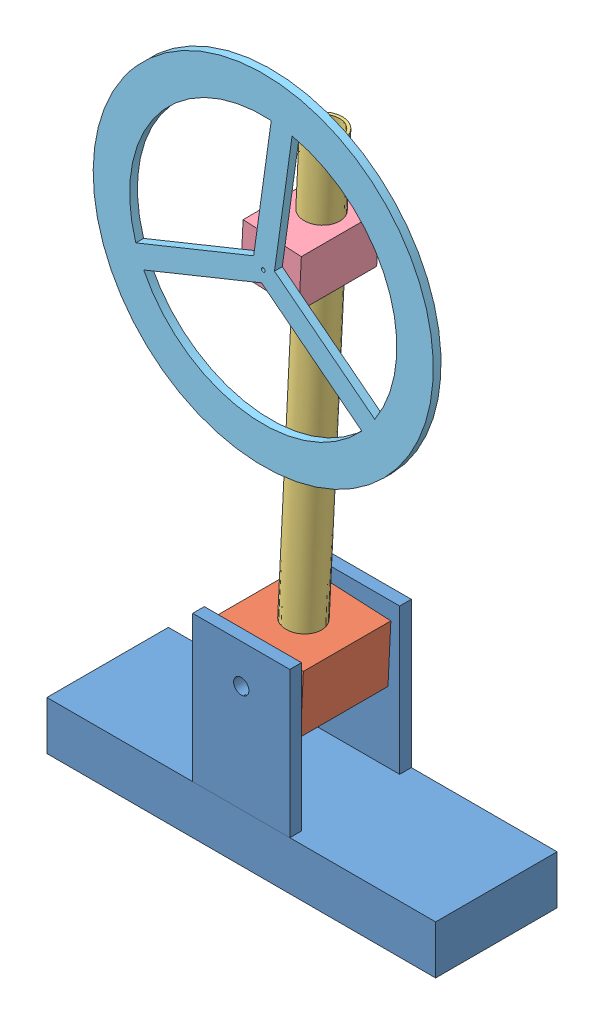
SolidWorks assembly final, configuration Default. Lengths in mm.
Overall size (491.23 784.15 125).
5 component instances, 5 part files, 9 mates.
Components (placement in the parent):
- wooden-base-1: wooden-base [Default] at (384.7333 86.1803 366.1694) size (400 200 125)
- first-1: first [Default] at (138.2963 218.4566 303.6694) x (0.998761 -0.049758 0) z (0 0 1) size (90 60 90)
- cylinder(1)-1: cylinder(1) [Default] at (186.1763 275.1444 303.6694) x (0.998761 -0.049758 0) z (0 0 1) size (37.5 450 37.5)
- mod1-1: mod1 [Default] at (173.6288 626.2036 354.4194) x (0.998761 -0.049758 0) z (0 0 1) size (60 50 80)
- wheel-1: wheel [Default] at (203.5917 624.7108 354.4194) x (-0.788528 0.614999 0) z (0 0 1) size (350 350 8)
Mates (geometry in assembly coordinates):
- Concentric1: concentric aligned: circle of wooden-base-1; circle of first-1
- Distance1: distance = 5.5 mm anti-aligned: plane of first-1 through (138.2963 218.4566 348.6694) normal (0 0 1); plane of wooden-base-1 through (134.7333 286.1803 354.1694) normal (0 0 -1)
- Coincident3: coincident anti-aligned: plane of first-1 through (186.1763 275.1444 303.6694) normal (0.049758 0.998761 0); plane of cylinder(1)-1 through (170.4458 275.9281 303.6694) normal (-0.049758 -0.998761 0)
- Concentric2: concentric anti-aligned: cylinder of first-1 through (186.1763 275.1444 303.6694) axis (0.049758 0.998761 0) radius 18.75; cylinder of cylinder(1)-1 through (186.1763 275.1444 303.6694) axis (-0.049758 -0.998761 0) radius 18.75
- Concentric15: concentric aligned: cylinder of cylinder(1)-1 through (186.1763 275.1444 303.6694) axis (-0.049758 -0.998761 0) radius 18.75; cylinder of mod1-1 through (204.8356 649.6798 303.6694) axis (-0.049758 -0.998761 0) radius 18.75
- Concentric16: concentric anti-aligned: cylinder of cylinder(1)-1 through (203.5917 624.7108 284.9194) axis (0 0 1) radius 12.4; cylinder of mod1-1 through (203.5917 624.7108 354.4194) axis (0 0 -1) radius 12.4
- Parallel8: parallel aligned: plane of wooden-base-1 through (234.7333 286.1803 366.1694) normal (0 0 1); plane of mod1-1 through (174.8728 651.1726 354.4194) normal (0 0 1)
- Concentric17: concentric anti-aligned: cylinder of mod1-1 through (203.5917 624.7108 354.4194) axis (0 0 -1) radius 12.4; circle of wheel-1
- Coincident5: coincident anti-aligned: plane of mod1-1 through (174.8728 651.1726 354.4194) normal (0 0 1); plane of wheel-1 through (203.5917 624.7108 354.4194) normal (0 0 -1)
